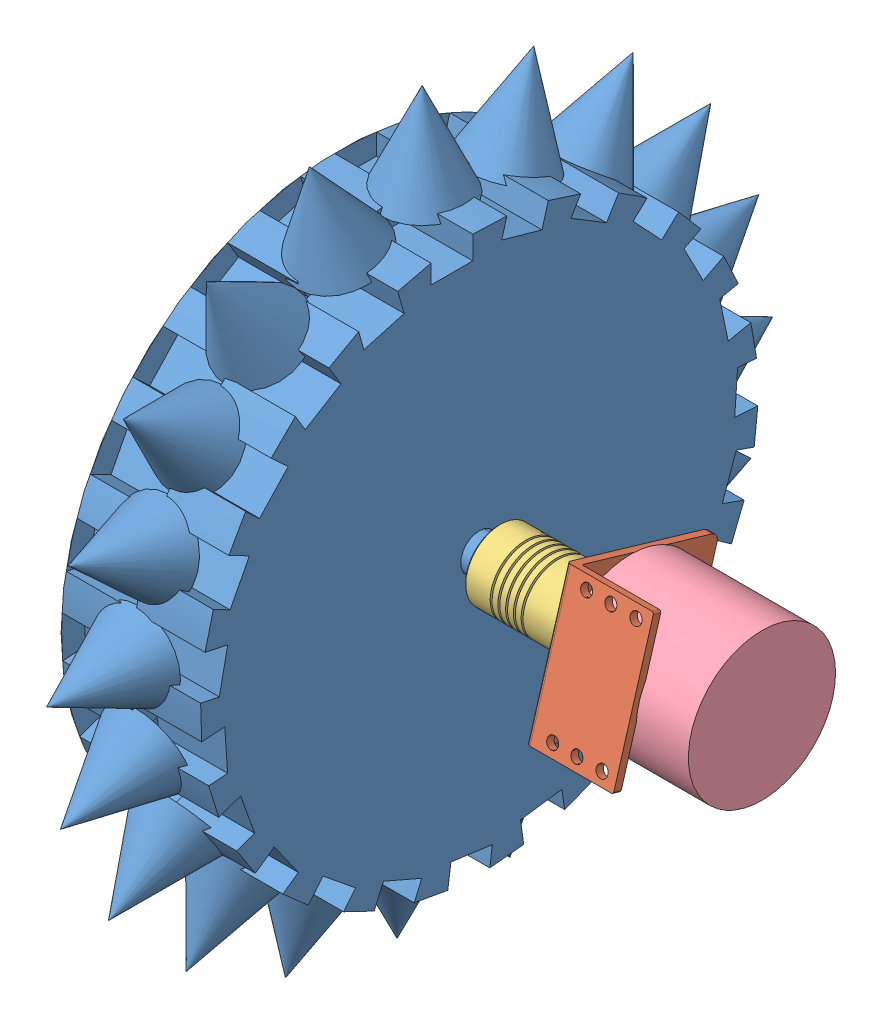
SolidWorks assembly assembly, configuration Default. Lengths in mm.
Overall size (109 187.57 187.57).
4 component instances, 4 part files, 6 mates.
Components (placement in the parent):
- CR Wheel-1: CR Wheel [Default] at (7.7577 116.0544 123.2459) size (54 187.57 187.57)
- DCclamp-1: DCclamp [Default] at (64.7426 103.5384 146.2208) x (1 0 0) z (0 0.959216 -0.282674) size (22.5 39 37)
- flex coupler-1: flex coupler [Default] at (30.7426 116.0544 123.2459) x (0 -0.580617 -0.814177) z (0 -0.814177 0.580617) size (18.93 24 18)
- Rotary_Encoder-1: Rotary_Encoder [Default] at (98.7426 116.0544 123.2459) x (0 -0.905947 0.42339) z (-1 0 0) size (38 38 51)
Mates (geometry in assembly coordinates):
- Concentric1: concentric: cylinder of DCclamp-1 through (54.7426 116.0544 123.2459) axis (1 0 0) radius 13.8601; cylinder of Rotary_Encoder-1 through (59.7426 116.0544 123.2459) axis (1 0 0) radius 10
- Coincident1: coincident: plane of DCclamp-1 through (64.7426 139.0294 135.7619) normal (1 0 0); plane of Rotary_Encoder-1 through (64.7426 116.0544 123.2459) normal (-1 0 0)
- Concentric2: concentric: cylinder of flex coupler-1 through (66.0563 116.0544 123.2459) axis (-1 0 0) radius 4; cylinder of Rotary_Encoder-1 through (47.7426 116.0544 123.2459) axis (1 0 0) radius 3
- Distance1: distance = 5 mm: plane of Rotary_Encoder-1 through (59.7426 116.0544 123.2459) normal (-1 0 0); plane of flex coupler-1 through (54.7426 116.0544 123.2459) normal (1 0 0)
- Concentric4: concentric: cylinder of CR Wheel-1 through (43.7426 116.0544 123.2459) axis (-1 0 0) radius 4.8; cylinder of flex coupler-1 through (54.7426 116.0544 123.2459) axis (-1 0 0) radius 9
- Distance2: distance = 5 mm: plane of CR Wheel-1 through (25.7426 116.0544 123.2459) normal (1 0 0); plane of flex coupler-1 through (30.7426 116.0544 123.2459) normal (-1 0 0)
